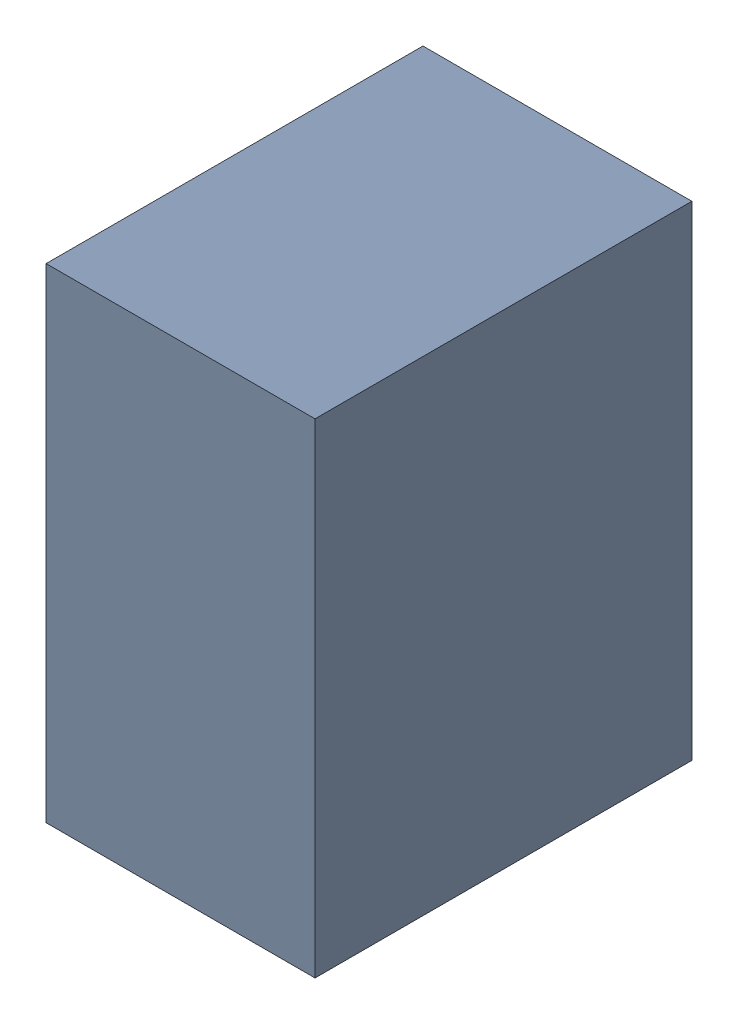
SolidWorks assembly C10, configuration Default. Lengths in mm.
Overall size (1 1.8 1.4).
3 component instances, 2 part files, 0 mates.
Components (placement in the parent):
- 1088883208-1: 1088883208 [Default] at (10.525 38.125 0) size (1 1.8 1.4)
  - Extruded-45-1: Extruded-45 [Default] at origin size (1 1.8 1.4)
- C0603-1: C0603 [Default] at (10.1249 38.925 0) x (0 -1 0) z (-1 0 0) size (1.6 0.5 0.8)
